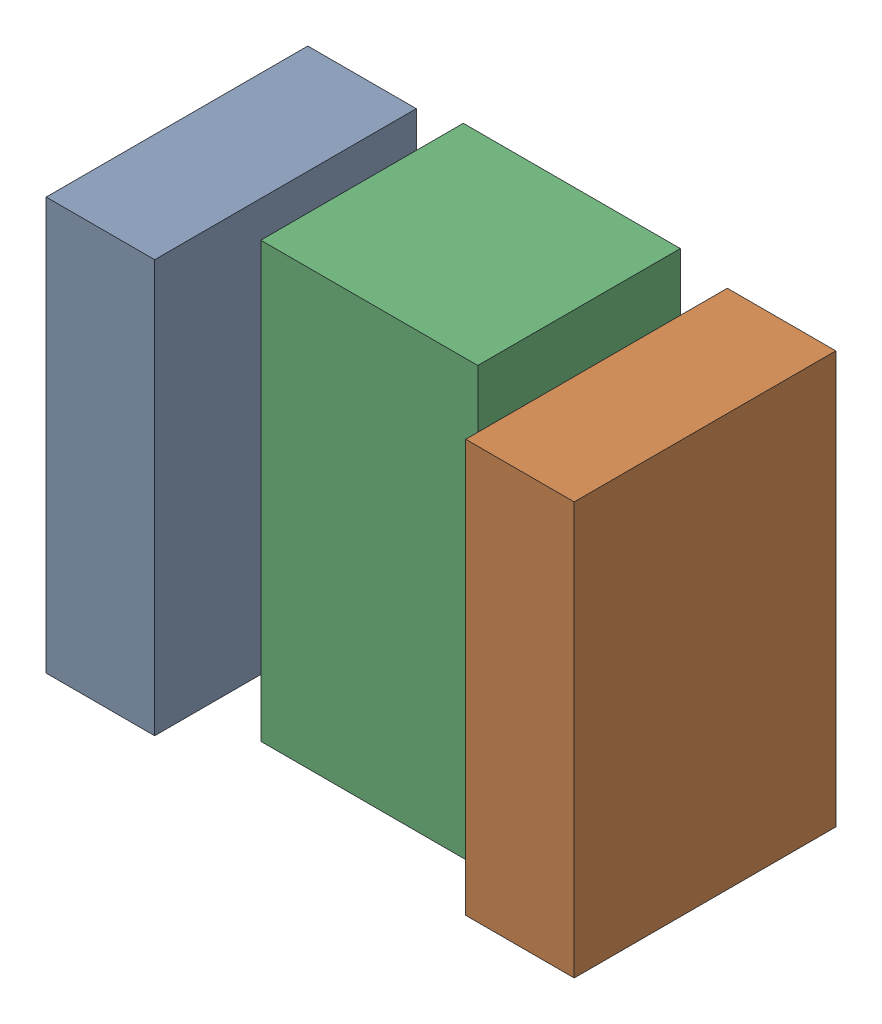
SolidWorks assembly C7_Motor_4Kanaloa_v2.0.0_Motor, configuration Default. Lengths in mm.
Overall size (3.65 3 1.81).
6 component instances, 2 part files, 0 mates.
Components (placement in the parent):
- 334788400-1: 334788400 [Default] at (102.257 84.582 0) size (0.75 2.85 1.81)
  - Extruded_5-1: Extruded_5 [Default] at origin size (0.75 2.85 1.81)
- 334788400-2: 334788400 [Default] at (105.157 84.582 0) size (0.75 2.85 1.81)
  - Extruded_5-1: Extruded_5 [Default] at origin size (0.75 2.85 1.81)
- 334788656-1: 334788656 [Default] at (103.707 84.582 0) size (1.5 3 1.4)
  - Extruded_1-1: Extruded_1 [Default] at origin size (1.5 3 1.4)
